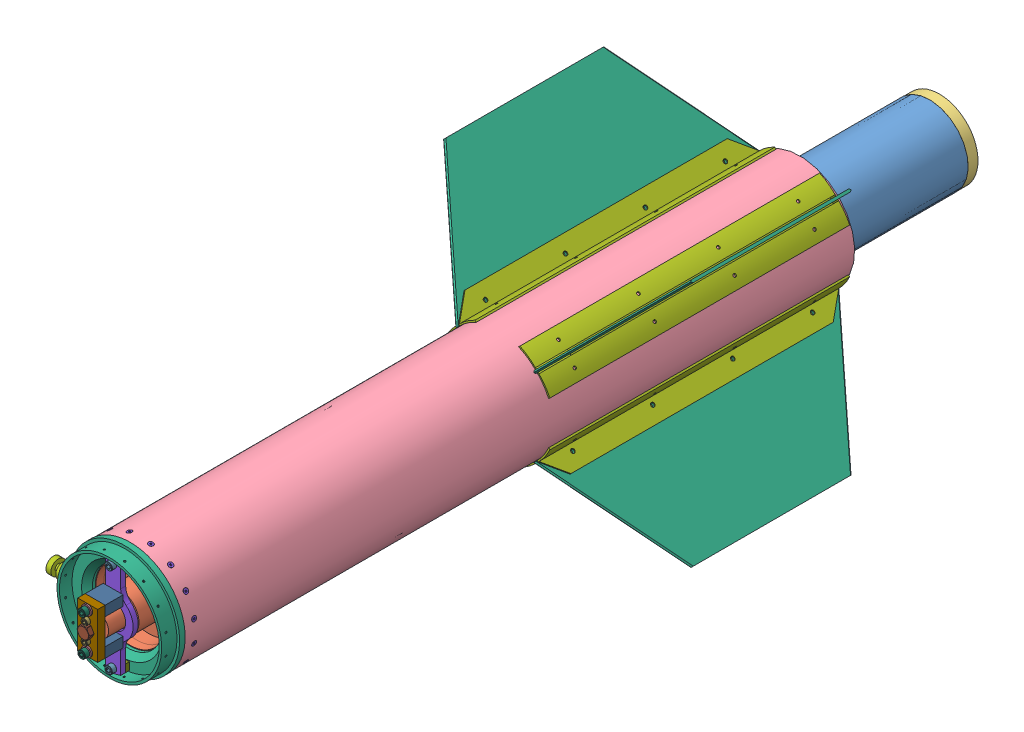
SolidWorks assembly Copy of RouseTech_Motor_Retainmenta_Asm, configuration Default. Lengths in mm.
Overall size (316.55 316.55 1102.99).
68 component instances, 28 part files, 35 mates.
Components (placement in the parent):
- RouseTech_15360_Motor_Casing-1: RouseTech_15360_Motor_Casing [Default] at (0 0 12.7) x (0.954187 -0.29921 0) z (0 0 1) size (98.42 98.42 1005.33)
- RouseTech_98mm_Forward_Closure-1: RouseTech_98mm_Forward_Closure [Default] at (0 0 985.1263) x (-1 0.000002 0) z (0 0 1) size (98.27 98.27 85.09)
- RouseTech_98mm_Aft_Closure-1: RouseTech_98mm_Aft_Closure [Default] x (-1 0.000002 0) z (0 0 1) size (98 98 35.31)
- Motor_Fairing-1: Motor_Fairing [Default] at (0 0 1028.4841) x (0.980785 -0.19509 0) z (0 0 -1) size (139.7 139.7 850.9)
- Aft_Motor_Centering_Ring-1: Aft_Motor_Centering_Ring [Default] at (0 0 177.5968) x (0 -1 0) z (0 0 1) size (136.27 136.27 15.88)
- Motor_Bulkhead-1: Motor_Bulkhead [Default] at (0 0 1008.9261) x (-0.19509 -0.980785 0) z (0 0 1) size (139.7 139.7 46.1)
- Launch_Lug-1: Launch_Lug [Default] at (-69.1975 0 1032.0401) x (0 1 0) z (-1 0 0) size (19.05 19.05 25.33)
- Launch_Lug-2: Launch_Lug [Default] at (-69.1975 0 188.7093) x (0 1 0) z (-1 0 0) size (19.05 19.05 25.33)
- RouseTech_Retainer_Bracket2-1: RouseTech_Retainer_Bracket2 [Default] at (13.9486 -3.8393 1028.2531) x (0 1 0) z (0 0 1) size (127 50.8 67.37)
  - Retainment_Strap-1: Retainment_Strap [Default] at (-59.6607 23.4736 15.5345) size (127 50.8 6.35)
  - RouseTech_Retaining_CrossBar2-1: RouseTech_Retaining_CrossBar2 [Default] at (33.0493 13.9486 49.507) x (0 -1 0) z (-1 0 0) size (25.4 9.53 58.42)
  - Motor_Retainer_Standoff-1: Motor_Retainer_Standoff [Default] at (-19.0207 13.9486 21.8845) x (0 -1 0) z (0 0 1) size (25.4 12.7 22.86)
  - Motor_Retainer_Standoff-2: Motor_Retainer_Standoff [Default] at (26.6993 13.9486 21.8845) x (0 1 0) z (0 0 1) size (25.4 12.7 22.86)
  - 0.375in-16_1.25in_Bolt_MC-92620A626-1: 0.375in-16_1.25in_Bolt_MC-92620A626 [92620A626] at (3.8393 13.9486 38.3945) size (14.29 16.24 37.79)
  - 10-24_0.375in_Allen_Head_Cap_Screw_MC-91251A240-1: 10-24_0.375in_Allen_Head_Cap_Screw_MC-91251A240 [91251A240] at (-7.2097 13.9486 44.7445) x (-0.923728 -0.383049 0) z (0 0 -1) size (7.92 7.92 15.51)
  - 10-24_0.375in_Allen_Head_Cap_Screw_MC-91251A240-2: 10-24_0.375in_Allen_Head_Cap_Screw_MC-91251A240 [91251A240] at (14.8883 13.9486 44.7445) x (-0.923728 -0.383049 0) z (0 0 -1) size (7.92 7.92 15.51)
  - 0.25in_Lock_Washer-1: 0.25in_Lock_Washer [Default] at (26.6993 13.9486 56.1237) x (-0.923728 -0.383049 0) z (0 0 -1) size (12.32 12.32 1.85)
  - 0.25in_Lock_Washer-2: 0.25in_Lock_Washer [Default] at (-19.0207 13.9486 56.1237) x (-0.923728 -0.383049 0) z (0 0 -1) size (12.32 12.32 1.85)
  - 0.25-20_1.0in_Allen Head_Cap_Screw_MC-91251A542-1: 0.25-20_1.0in_Allen Head_Cap_Screw_MC-91251A542 [91251A542] at (60.9893 13.9486 -3.5155) x (-0.923728 -0.383049 0) z (0 0 -1) size (9.53 9.53 33.14)
  - 0.25-20_1.0in_Allen Head_Cap_Screw_MC-91251A542-2: 0.25-20_1.0in_Allen Head_Cap_Screw_MC-91251A542 [91251A542] at (-53.3107 13.9486 -3.5155) x (-0.923728 -0.383049 0) z (0 0 -1) size (9.53 9.53 33.14)
  - 0.25-20_1.75in_Allen Head_Cap_Screw_MC-91251A548-1: 0.25-20_1.75in_Allen Head_Cap_Screw_MC-91251A548 [91251A548] at (26.6993 13.9486 11.6737) x (-0.923728 -0.383049 0) z (0 0 -1) size (9.53 9.53 52.19)
  - 0.25-20_1.75in_Allen Head_Cap_Screw_MC-91251A548-2: 0.25-20_1.75in_Allen Head_Cap_Screw_MC-91251A548 [91251A548] at (-19.0207 13.9486 11.6737) x (-0.950943 -0.309366 0) z (0 0 -1) size (9.53 9.53 52.19)
  - RouseTech_Retainer_Spacer-1: RouseTech_Retainer_Spacer [Default] at (60.2908 13.9486 10.772) x (0 -1 0) z (0 0 1) size (19.05 9.53 4.76)
  - RouseTech_Retainer_Spacer-2: RouseTech_Retainer_Spacer [Default] at (-52.6122 13.9486 10.772) x (0 1 0) z (0 0 1) size (19.05 9.53 4.76)
- N2000W_Reload_Assembeled-1: N2000W_Reload_Assembeled [Default] at (0 0 56.2356) x (-0.683365 0.730076 0) z (0.730076 0.683365 0) size (129.43 1050.01 129.43)
  - N2000W_Grain-1: N2000W_Grain [Default] at origin size (85.22 152.4 85.22)
  - N2000W_Grain-2: N2000W_Grain [Default] at (0 457.2 0) x (0.999641 0 -0.02679) z (0.02679 0 0.999641) size (85.22 152.4 85.22)
  - N2000W_Grain-3: N2000W_Grain [Default] at (0 152.4 0) size (85.22 152.4 85.22)
  - N2000W_Grain-4: N2000W_Grain [Default] at (0 609.6 0) x (0.569996 0 0.821647) z (-0.821647 0 0.569996) size (85.22 152.4 85.22)
  - N2000W_Grain-6: N2000W_Grain [Default] at (0 304.8 0) size (85.22 152.4 85.22)
  - N2000W_Reload_Liner-1: N2000W_Reload_Liner [Default] at (0 -9.144 0) x (0.685714 0 0.727871) z (-0.727871 0 0.685714) size (91.16 936.62 91.16)
  - N2000W_Grain-7: N2000W_Grain [Default] at (0 762 0) size (85.22 152.4 85.22)
  - N2000W_Nozel-1: N2000W_Nozel [Default] at (0 -42.8244 0) x (-0.670154 0 -0.742222) z (-0.742222 0 0.670154) size (91.64 68.22 91.64)
  - N2000W_O_Ring-1: N2000W_O_Ring [Default] at (0 -18.3388 0) x (-0.992176 0 0.124851) z (0.124851 0 0.992176) size (92.2 5.18 92.2)
  - N2000W_O_Ring-2: N2000W_O_Ring [Default] at (0 933.577 0) x (0.982844 0 -0.18444) z (0.18444 0 0.982844) size (92.2 5.18 92.2)
  - N2000W_Forward_Seal_Disc-1: N2000W_Forward_Seal_Disc [Default] at (0 930.9862 0) size (92.15 7.62 92.15)
  - Part7^N2000W_Reload_Assembeled-1: Part7^N2000W_Reload_Assembeled [Default] at origin (virtual)
  - Part8^N2000W_Reload_Assembeled-1: Part8^N2000W_Reload_Assembeled [Default] at origin (virtual)
  - N2000W_Smoke_Grain-1: N2000W_Smoke_Grain [Default] at (0 930.9862 0) x (1 0 0) z (0 1 0) size (32.89 32.89 50.75)
  - N2000W_Smoke_Grain_Liner-1: N2000W_Smoke_Grain_Liner [Default] at (0 930.9862 0) x (1 0 0) z (0 1 0) size (38.1 38.1 50.8)
- Fin-1: Fin [Default] at (-49.3914 49.3914 371.2591) x (0 0 1) z (-0.707107 -0.707107 0) size (387.35 152.4 3.17)
- Fin-4: Fin [Default] at (49.3914 49.3914 371.2591) x (0 0 1) z (-0.707107 0.707107 0) size (387.35 152.4 3.17)
- Fin-3: Fin [Default] at (49.3914 -49.3914 371.2591) x (0 0 1) z (0.707107 0.707107 0) size (387.35 152.4 3.17)
- Fin-2: Fin [Default] at (-49.3914 -49.3914 371.2591) x (0 0 1) z (0.707107 -0.707107 0) size (387.35 152.4 3.17)
- Fin_Clamp_Half-1: Fin_Clamp_Half [Default] at (-48.2689 50.5139 371.2591) x (0.707107 0.707107 0) z (0 0 1) size (25.4 30.18 381)
- Fin_Clamp_Half-2: Fin_Clamp_Half [Default] at (-50.5139 48.2689 371.2591) x (-0.707107 -0.707107 0) z (0 0 -1) size (25.4 30.18 381)
- Fin_Clamp_Half-3: Fin_Clamp_Half [Default] at (-48.2689 -50.5139 371.2591) x (0.707107 -0.707107 0) z (0 0 -1) size (25.4 30.18 381)
- Fin_Clamp_Half-4: Fin_Clamp_Half [Default] at (50.5139 -48.2689 371.2591) x (0.707107 0.707107 0) z (0 0 -1) size (25.4 30.18 381)
- Fin_Clamp_Half-5: Fin_Clamp_Half [Default] at (48.2689 50.5139 371.2591) x (-0.707107 0.707107 0) z (0 0 -1) size (25.4 30.18 381)
- Fin_Clamp_Half-6: Fin_Clamp_Half [Default] at (-50.5139 -48.2689 371.2591) x (-0.707107 0.707107 0) z (0 0 1) size (25.4 30.18 381)
- Fin_Clamp_Half-7: Fin_Clamp_Half [Default] at (48.2689 -50.5139 371.2591) x (-0.707107 -0.707107 0) z (0 0 1) size (25.4 30.18 381)
- Fin_Clamp_Half-8: Fin_Clamp_Half [Default] at (50.5139 48.2689 371.2591) x (0.707107 -0.707107 0) z (0 0 1) size (25.4 30.18 381)
- 3.0mm_8mm_Counter_Sunk_Hex_Screw-1: 3.0mm_8mm_Counter_Sunk_Hex_Screw [91294A128] at (-34.4176 51.5095 1015.7841) x (0.691343 0.46194 -0.555569) z (0.55557 -0.83147 0) size (6 6 8.55)
- 3.0mm_8mm_Counter_Sunk_Hex_Screw-2: 3.0mm_8mm_Counter_Sunk_Hex_Screw [91294A128] at (-51.5095 34.4176 1015.7841) x (0.46194 0.691343 -0.555569) z (0.83147 -0.55557 0) size (6 6 8.55)
- 3.0mm_8mm_Counter_Sunk_Hex_Screw-3: 3.0mm_8mm_Counter_Sunk_Hex_Screw [91294A128] at (-60.7596 12.0858 1015.7841) x (0.162212 0.815494 -0.555569) z (0.980785 -0.19509 0) size (6 6 8.55)
- 3.0mm_8mm_Counter_Sunk_Hex_Screw-4: 3.0mm_8mm_Counter_Sunk_Hex_Screw [91294A128] at (-60.7596 -12.0858 1015.7841) x (-0.162212 0.815494 -0.555569) z (0.980785 0.19509 0) size (6 6 8.55)
- 3.0mm_8mm_Counter_Sunk_Hex_Screw-5: 3.0mm_8mm_Counter_Sunk_Hex_Screw [91294A128] at (-51.5095 -34.4176 1015.7841) x (-0.46194 0.691343 -0.555569) z (0.83147 0.55557 0) size (6 6 8.55)
- 3.0mm_8mm_Counter_Sunk_Hex_Screw-6: 3.0mm_8mm_Counter_Sunk_Hex_Screw [91294A128] at (-34.4176 -51.5095 1015.7841) x (-0.691343 0.46194 -0.555569) z (0.55557 0.83147 0) size (6 6 8.55)
- 3.0mm_8mm_Counter_Sunk_Hex_Screw-7: 3.0mm_8mm_Counter_Sunk_Hex_Screw [91294A128] at (-12.0858 -60.7596 1015.7841) x (-0.815494 0.162212 -0.555569) z (0.19509 0.980785 0) size (6 6 8.55)
- 3.0mm_8mm_Counter_Sunk_Hex_Screw-8: 3.0mm_8mm_Counter_Sunk_Hex_Screw [91294A128] at (12.0858 -60.7596 1015.7841) x (-0.815494 -0.162212 -0.555569) z (-0.19509 0.980785 0) size (6 6 8.55)
- 3.0mm_8mm_Counter_Sunk_Hex_Screw-9: 3.0mm_8mm_Counter_Sunk_Hex_Screw [91294A128] at (34.4176 -51.5095 1015.7841) x (-0.691343 -0.46194 -0.555569) z (-0.55557 0.83147 0) size (6 6 8.55)
- 3.0mm_8mm_Counter_Sunk_Hex_Screw-10: 3.0mm_8mm_Counter_Sunk_Hex_Screw [91294A128] at (51.5095 -34.4176 1015.7841) x (-0.46194 -0.691343 -0.555569) z (-0.83147 0.55557 0) size (6 6 8.55)
- 3.0mm_8mm_Counter_Sunk_Hex_Screw-11: 3.0mm_8mm_Counter_Sunk_Hex_Screw [91294A128] at (60.7596 -12.0858 1015.7841) x (-0.162212 -0.815494 -0.555569) z (-0.980785 0.19509 0) size (6 6 8.55)
- 3.0mm_8mm_Counter_Sunk_Hex_Screw-12: 3.0mm_8mm_Counter_Sunk_Hex_Screw [91294A128] at (60.7596 12.0858 1015.7841) x (0.162212 -0.815494 -0.555569) z (-0.980785 -0.19509 0) size (6 6 8.55)
- 3.0mm_8mm_Counter_Sunk_Hex_Screw-13: 3.0mm_8mm_Counter_Sunk_Hex_Screw [91294A128] at (51.5095 34.4176 1015.7841) x (0.46194 -0.691343 -0.555569) z (-0.83147 -0.55557 0) size (6 6 8.55)
- 3.0mm_8mm_Counter_Sunk_Hex_Screw-14: 3.0mm_8mm_Counter_Sunk_Hex_Screw [91294A128] at (34.4176 51.5095 1015.7841) x (0.691343 -0.46194 -0.555569) z (-0.55557 -0.83147 0) size (6 6 8.55)
- 3.0mm_8mm_Counter_Sunk_Hex_Screw-15: 3.0mm_8mm_Counter_Sunk_Hex_Screw [91294A128] at (12.0858 60.7596 1015.7841) x (0.815494 -0.162212 -0.555569) z (-0.19509 -0.980785 0) size (6 6 8.55)
- 3.0mm_8mm_Counter_Sunk_Hex_Screw-16: 3.0mm_8mm_Counter_Sunk_Hex_Screw [91294A128] at (-12.0858 60.7596 1015.7841) x (0.815494 0.162212 -0.555569) z (0.19509 -0.980785 0) size (6 6 8.55)
Mates (geometry in assembly coordinates):
- Coincident1: coincident aligned: axis of RouseTech_98mm_Aft_Closure-1 through (0 0 35.306) axis (0 0 -1); axis of RouseTech_15360_Motor_Casing-1 through (0 0 1018.032) axis (0 0 -1)
- Coincident2: coincident anti-aligned: plane of RouseTech_98mm_Aft_Closure-1 through (0 0 12.7) normal (0 0 1); plane of RouseTech_15360_Motor_Casing-1 through (0 0 12.7) normal (0 0 -1)
- Coincident3: coincident aligned: axis of RouseTech_98mm_Forward_Closure-1 through (0 0 1018.032) axis (0 0 -1); axis of RouseTech_15360_Motor_Casing-1 through (0 0 1018.032) axis (0 0 -1)
- Coincident4: coincident anti-aligned: plane of RouseTech_98mm_Forward_Closure-1 through (0 0 1018.032) normal (0 0 -1); plane of RouseTech_15360_Motor_Casing-1 through (0 0 1018.032) normal (0 0 1)
- Coincident7: coincident anti-aligned: axis of RouseTech_15360_Motor_Casing-1 through (0 0 1018.032) axis (0 0 -1); axis of Motor_Fairing-1 through (0 0 177.5841) axis (0 0 1)
- Parallel3: parallel: axis of RouseTech_15360_Motor_Casing-1 through (0 0 1018.032) axis (0 0 -1); plane of assembly
- Coincident54: coincident aligned: axis of RouseTech_98mm_Forward_Closure-1 through (0 0 1041.2603) axis (0 0 1); axis of Motor_Bulkhead-1 through (0 0 1028.4841) axis (0 0 1)
- Coincident56: coincident anti-aligned: plane of RouseTech_98mm_Forward_Closure-1 through (0 0 1028.4841) normal (0 0 1); plane of Motor_Bulkhead-1 through (0 0 1028.4841) normal (0 0 -1)
- Parallel4: parallel: plane of assembly through (0 0 0) normal (0 1 0); axis of Motor_Bulkhead-1 through (-57.15 0 1032.0401) axis (-1 0 0)
- Coincident88: coincident anti-aligned: axis of Motor_Bulkhead-1 through (-57.15 0 1032.0401) axis (-1 0 0); axis of Launch_Lug-1 through (-81.5851 0 1032.0401) axis (1 0 0)
- Concentric1: concentric anti-aligned: cylinder of Motor_Bulkhead-1 through (0 0 1055.0271) axis (0 0 -1) radius 69.85; cylinder of Launch_Lug-1 through (0 0 986.2827) axis (0 0 1) radius 69.85
- Coincident89: coincident anti-aligned: plane of Motor_Fairing-1; plane of Fin-1 through (-49.3914 49.3914 371.2591) normal (-0.707107 -0.707107 0)
- Parallel8: parallel aligned: axis of Motor_Fairing-1 through (0 0 177.5841) axis (0 0 1); line of Fin-1 through (-48.2689 50.5139 179.2163) axis (0 0 1)
- Tangent1: tangent anti-aligned: cylinder of Motor_Fairing-1 through (0 0 177.5841) axis (0 0 1) radius 69.85; plane of Fin-1 through (-50.5139 48.2689 371.2591) normal (0.707107 -0.707107 0)
- Coincident92: coincident anti-aligned: axis of Motor_Fairing-1 through (-68.2148 0 188.7093) axis (-1 0 0); axis of Aft_Motor_Centering_Ring-1 through (61.7855 0 188.7093) axis (1 0 0)
- Coincident93: coincident aligned: axis of RouseTech_15360_Motor_Casing-1 through (0 0 1018.032) axis (0 0 -1); axis of Aft_Motor_Centering_Ring-1 through (0 0 183.9468) axis (0 0 -1)
- Coincident99: coincident anti-aligned: axis of Motor_Fairing-1 through (-68.2148 0 188.7093) axis (-1 0 0); axis of Launch_Lug-2 through (-81.5851 0 188.7093) axis (1 0 0)
- Concentric2: concentric aligned: cylinder of Motor_Fairing-1 through (0 0 177.5841) axis (0 0 1) radius 69.85; cylinder of Launch_Lug-2 through (0 0 142.9519) axis (0 0 1) radius 69.85
- Coincident102: coincident anti-aligned: axis of Motor_Fairing-1 through (-68.4738 13.6203 1015.7841) axis (0.980785 -0.19509 0); axis of Motor_Bulkhead-1 through (-63.787 12.688 1015.7841) axis (-0.980785 0.19509 0)
- Coincident103: coincident: circle of Motor_Fairing-1; moEndPointRef_w of Fin-1
- Coincident106: coincident anti-aligned: axis of RouseTech_98mm_Forward_Closure-1 through (0 0 1043.5463) axis (0 0 1); axis of RouseTech_Retainer_Bracket2-1/Retainment_Strap-1 through (0 0 1050.1376) axis (0 0 -1)
- Coincident107: coincident aligned: axis of Motor_Bulkhead-1 through (0 -57.15 1018.4511) axis (0 0 1); axis of RouseTech_Retainer_Bracket2-1/Retainment_Strap-1 through (0 -57.15 1043.7876) axis (0 0 1)
- Coincident108: coincident anti-aligned: plane of Motor_Bulkhead-1 through (0 0 1039.0251) normal (0 0 1); plane of RouseTech_Retainer_Bracket2-1/RouseTech_Retainer_Spacer-2 through (-9.525 -61.214 1039.0251) normal (0 0 -1)
- Coincident109: coincident aligned: axis of RouseTech_15360_Motor_Casing-1 through (0 0 1018.032) axis (0 0 -1); axis of N2000W_Reload_Assembeled-1/N2000W_Reload_Liner-1 through (0 0 983.7166) axis (0 0 -1)
- Coincident112: coincident anti-aligned: line of Fin-1 through (-48.2689 50.5139 179.2163) axis (0 0 1); line of Fin_Clamp_Half-1 through (-48.2689 50.5139 561.7591) axis (0 0 -1)
- Coincident113: coincident anti-aligned: plane of Fin-1 through (-48.2689 50.5139 564.9341) normal (0.707107 0.707107 0); plane of Fin_Clamp_Half-1 through (-48.2689 50.5139 561.7591) normal (-0.707107 -0.707107 0)
- Coincident114: coincident anti-aligned: plane of Fin-1 through (-50.5139 48.2689 564.9341) normal (-0.707107 -0.707107 0); plane of Fin_Clamp_Half-2 through (-50.5139 48.2689 180.7591) normal (0.707107 0.707107 0)
- Coincident115: coincident aligned: line of Fin-1 through (-50.5139 48.2689 179.2163) axis (0 0 1); line of Fin_Clamp_Half-2 through (-50.5139 48.2689 180.7591) axis (0 0 1)
- Coincident116: coincident aligned: plane of Fin_Clamp_Half-1 through (1.1225 1.1225 180.7591) normal (0 0 -1); plane of Fin_Clamp_Half-2 through (-1.1225 -1.1225 180.7591) normal (0 0 -1)
- Coincident118: coincident anti-aligned: plane of Fin-1; plane of Fin_Clamp_Half-2 through (-50.5139 48.2689 371.2591) normal (0 0 1)
- Coincident119: coincident aligned: axis of Motor_Fairing-1 through (-38.8066 58.0782 1015.7841) axis (0.55557 -0.83147 0); axis of 3.0mm_8mm_Counter_Sunk_Hex_Screw-1 through (-38.7232 57.9534 1015.7841) axis (0.55557 -0.83147 0)
- Coincident120: coincident: cone of Motor_Fairing-1 through (-38.8066 58.0782 1015.7841) axis (0.55557 -0.83147 0); circle of 3.0mm_8mm_Counter_Sunk_Hex_Screw-1
- Coincident122: coincident anti-aligned: plane of RouseTech_98mm_Aft_Closure-1 through (0 0 0) normal (0 0 -1); plane of assembly through (0 0 0) normal (0 0 1)
- Coincident123: coincident: axis of Motor_Fairing-1 through (0 0 177.5841) axis (0 0 1); point of assembly
- Tangent2: tangent: plane of RouseTech_98mm_Aft_Closure-1 through (0 0 35.306) normal (0 0 1); face of N2000W_Reload_Assembeled-1/N2000W_O_Ring-1
